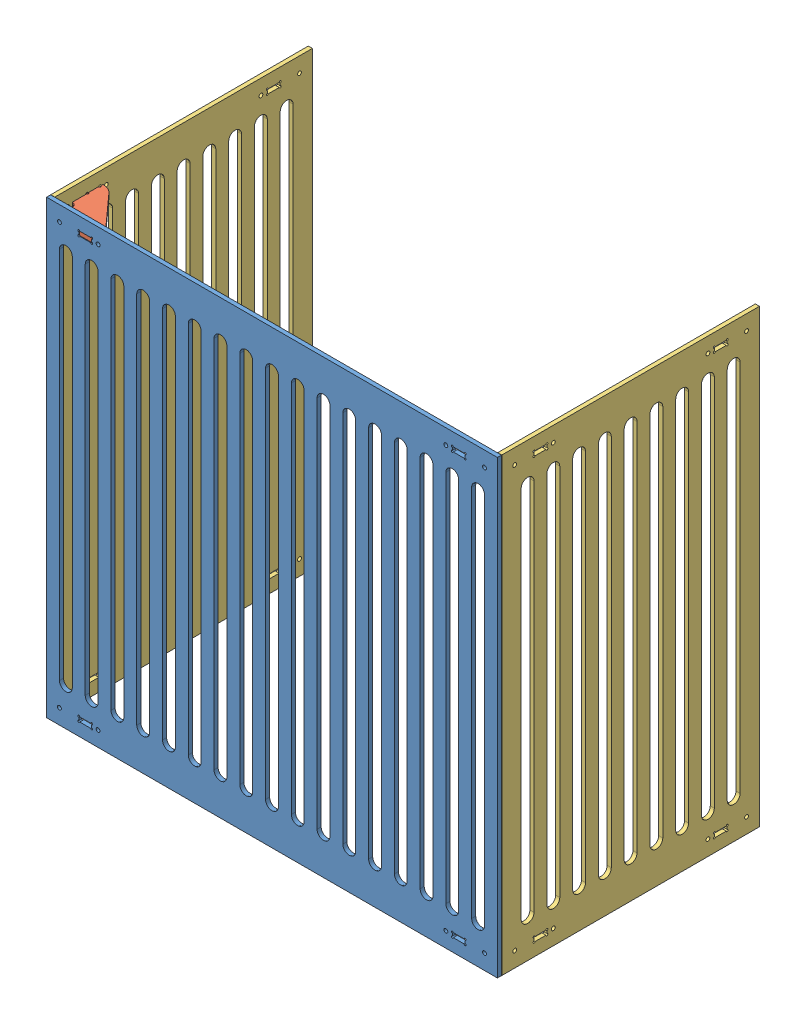
SolidWorks assembly 70cm_cover, configuration Default. Lengths in mm.
Overall size (700.02 700.3 406.87).
4 component instances, 3 part files, 0 mates.
Components (placement in the parent):
- 700_front-1: 700_front [Default] at origin size (700 700 6.35)
- connector-1: connector [Default] at (-343.4577 323.463 -0.1086) size (74.02 6.35 80.34)
- 400_side-1: 400_side [Default] at (-349.9099 0.1711 -199.9622) x (0 0 1) z (1 0 0) size (400 700 6.35)
- 400_side-2: 400_side [Default] at (343.6749 -0.1251 -200.5227) x (0 0 -1) z (1 0 0) size (400 700 6.35)
